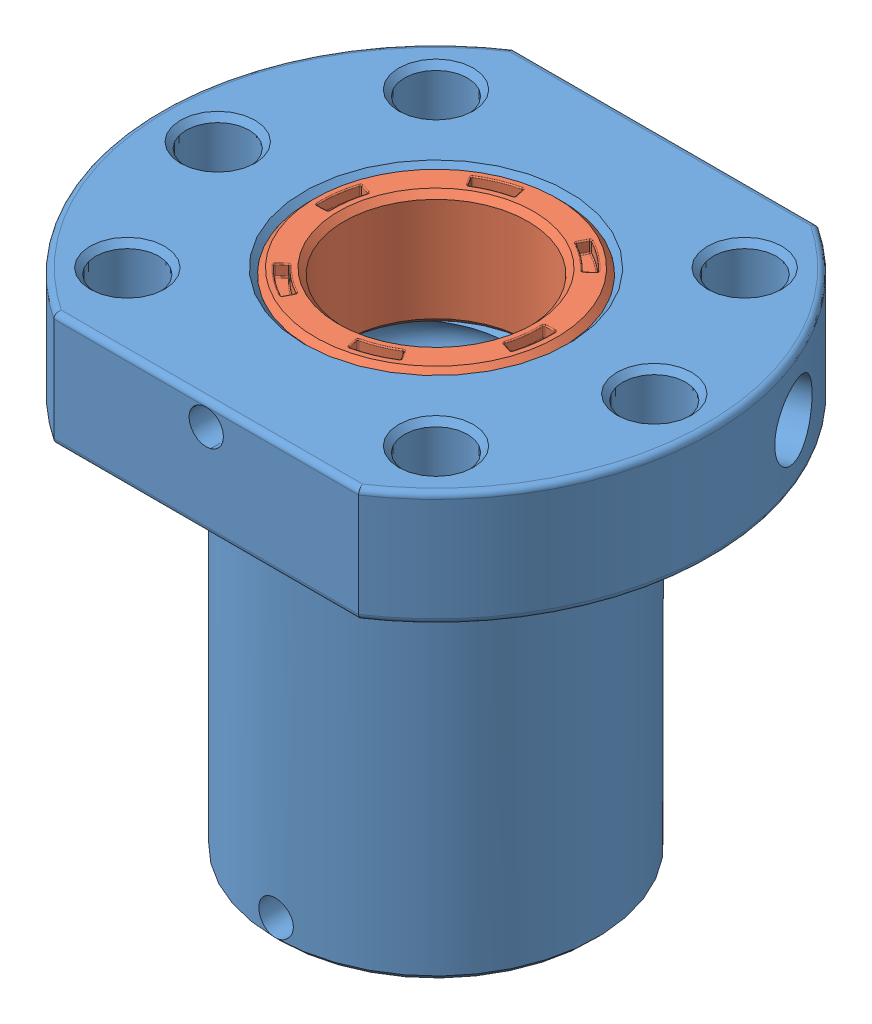
SolidWorks assembly SFU1605-1610 (2), configuration SFU1605-3. Lengths in mm.
Overall size (48 44 40).
3 component instances, 3 part files, 5 mates.
Components (placement in the parent):
- SFU1605-1610-1-1: SFU1605-1610-1 [Default] at (-14 43.5 0) size (48 44 40)
- SFU1605-1610-3-1: SFU1605-1610-3 [Default] at (-14 33.4998 0) x (-0.92388 0 0.382683) z (-0.382683 0 -0.92388) size (22.05 10 22)
- SFU1605-1610-2-1: SFU1605-1610-2 [Default] at (-14 9.5 0) x (1 0 0) z (0 0 -1) size (22 10 22)
Mates (geometry in assembly coordinates):
- Concentric1: concentric anti-aligned: cylinder of SFU1605-1610-1-1 through (-14 43.5 0) axis (0 1 0) radius 11; cylinder of SFU1605-1610-3-1 through (-14 43.4998 0) axis (0 -1 0) radius 11
- Concentric3: concentric anti-aligned: cylinder of SFU1605-1610-1-1 through (-41.5576 38.4998 11.4147) axis (0.92388 0 -0.382683) radius 2.5; cylinder of SFU1605-1610-3-1 through (-3.8364 38.4998 -4.2099) axis (-0.92388 0 0.382683) radius 2.5
- Coincident1: coincident anti-aligned: plane of SFU1605-1610-1-1 through (-14 9.5 8) normal (0 -1 0); plane of SFU1605-1610-2-1 through (-14 9.5 0) normal (0 1 0)
- Concentric4: concentric aligned: cylinder of SFU1605-1610-1-1 through (-14 43.5 0) axis (0 1 0) radius 11; cylinder of SFU1605-1610-2-1 through (-14 -0.5 0) axis (0 1 0) radius 11
- Coincident4: coincident: moEndPointRef_w of SFU1605-1610-1-1; point of assembly
